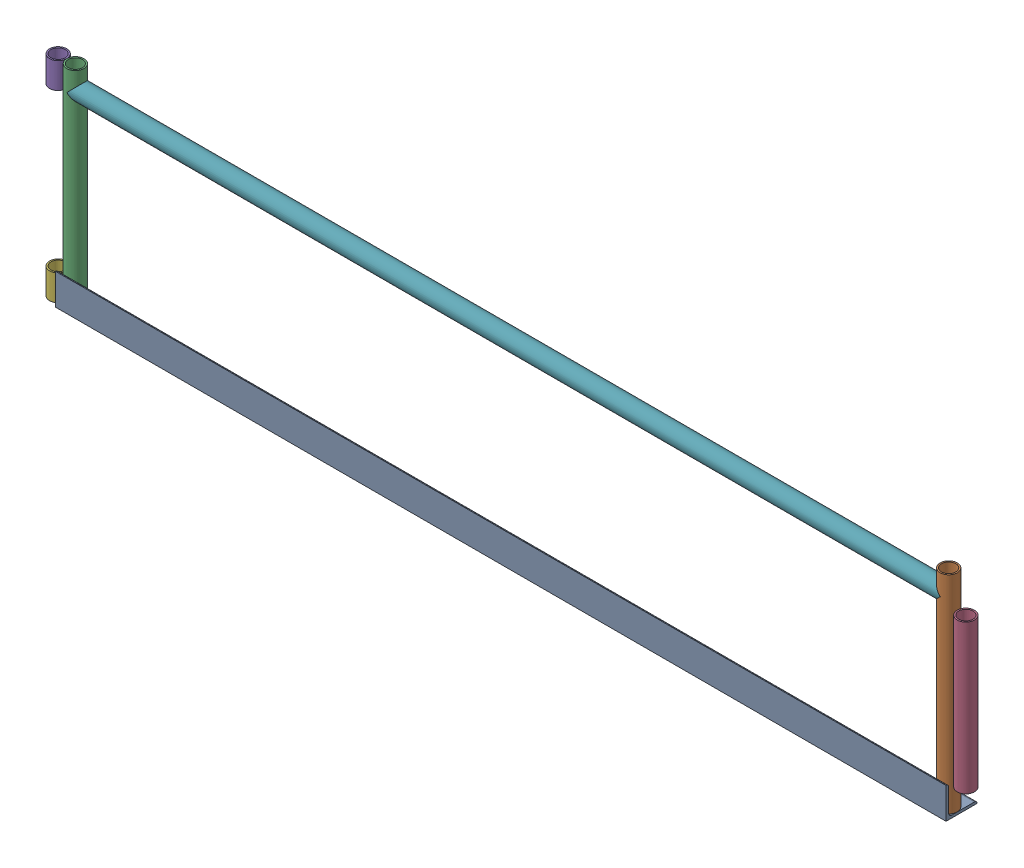
SolidWorks assembly GE-13015-R_ASM, configuration Default. Lengths in mm.
Overall size (2268.73 514.35 76.2).
7 component instances, 5 part files, 0 mates.
Components (placement in the parent):
- GE-13015-01-1: GE-13015-01 [Default] x (1 0 0) z (0 -1 0) size (2184.4 76.2 76.2)
- GE-13015-05-1: GE-13015-05 [Default] at (1071.118 260.35 -27.432) x (0 1 0) z (0 0 1) size (508 42.16 42.16)
- GE-13015-05-2: GE-13015-05 [Default] at (-1071.118 260.35 -27.432) x (0 1 0) z (0 0 1) size (508 42.16 42.16)
- GE-13015-04-1: GE-13015-04 [Default] at (1113.282 252.4125 -27.432) x (0 1 0) z (0 0 1) size (365.12 42.16 42.16)
- GE-13015-03-1: GE-13015-03 [Default] at (-1113.282 482.6 -27.432) x (0 -1 0) z (0 0 1) size (63.5 42.16 42.16)
- GE-13015-03-2: GE-13015-03 [Default] at (-1113.282 31.75 -27.432) x (0 -1 0) z (0 0 1) size (63.5 42.16 42.16)
- GE-13015-02-1: GE-13015-02 [Default] at (-1071.118 463.55 -27.432) size (2143.25 42.16 42.16)
